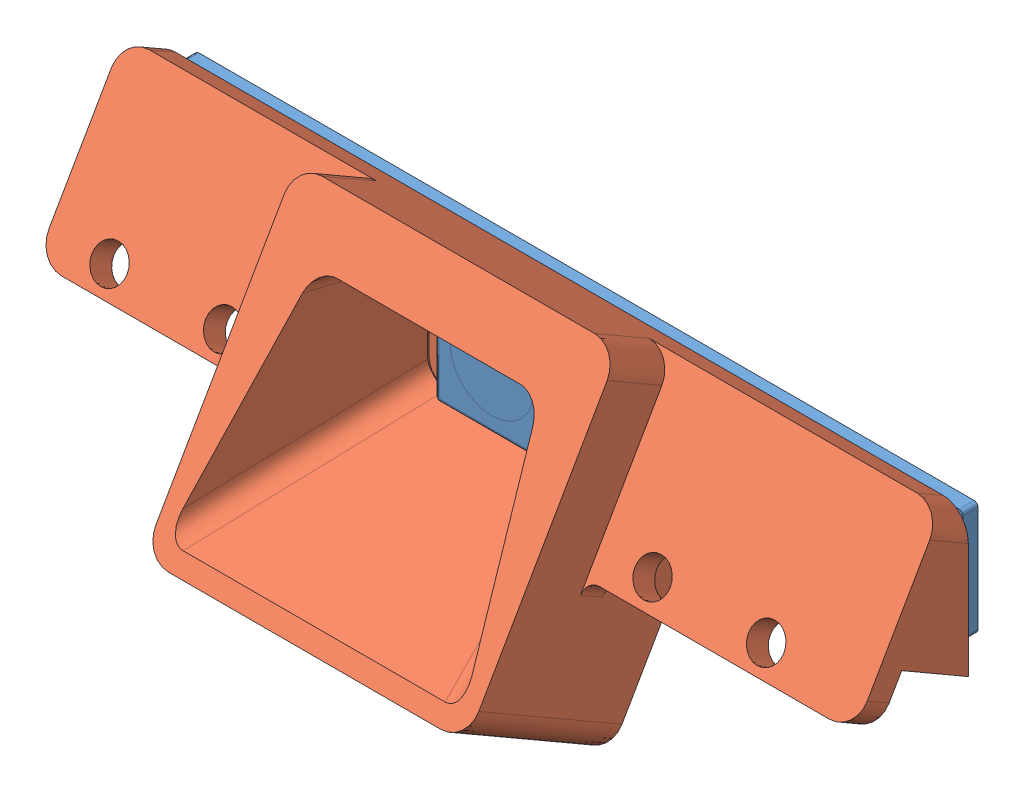
SolidWorks assembly setup_webcam, configuration Default. Lengths in mm.
Overall size (64.8 27.62 20.32).
2 component instances, 2 part files, 0 mates.
Components (placement in the parent):
- new_camera-1: new_camera [Default] at (-28.3825 87.6973 73.1787) size (62.8 9 5.5)
- webcam_box-2: webcam_box [Default] at (-33.3825 77.6973 74.9419) size (64.8 27.62 18.56)
